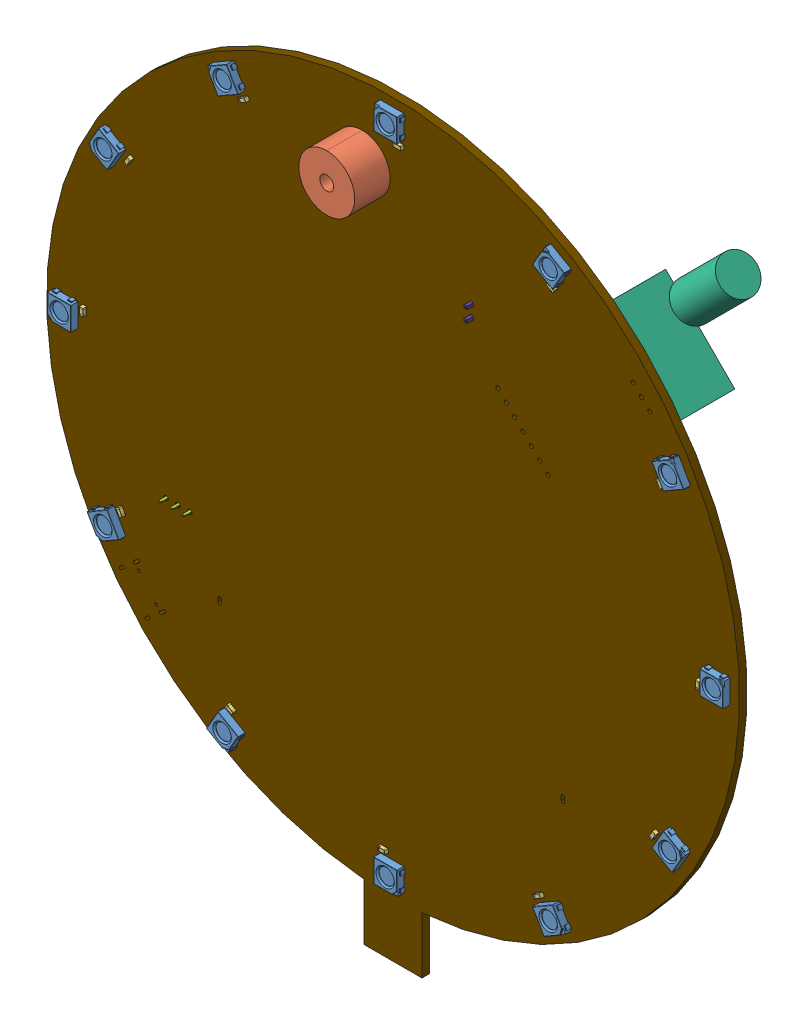
SolidWorks assembly Semafor2, configuration Výchozí. Lengths in mm.
Overall size (148.79 160.68 28.8).
170 component instances, 18 part files, 0 mates.
Components (placement in the parent):
- Semafor2.step-1: Semafor2.step [Výchozí] at origin size (148.79 160.68 28.8)
  - LED_WS2812B_PLCC4_5.0x5.0mm_P3.2mm.step-1: LED_WS2812B_PLCC4_5.0x5.0mm_P3.2mm.step [Výchozí] at (-39.4282 65.1 1.65) x (0.5 0.866025 0) z (0 0 1) size (5.4 5 1.6)
    - SOLID.step-1: SOLID.step [Výchozí] at origin size (5.4 5 1.6)
  - Piezo.step-1: Piezo.step [Výchozí] at (-106.6 158.895 1.65) x (1 0 0) z (0 -1 0) size (12 7.6 12)
    - SOLID-0.step-1: SOLID-0.step [Výchozí] at origin size (12 7.6 12)
  - LED_WS2812B_PLCC4_5.0x5.0mm_P3.2mm.step-2: LED_WS2812B_PLCC4_5.0x5.0mm_P3.2mm.step [Výchozí] at (-30.05 100.1 1.65) x (0 1 0) z (0 0 1) size (5.4 5 1.6)
    - SOLID.step-1: SOLID.step [Výchozí] at origin size (5.4 5 1.6)
  - LED_WS2812B_PLCC4_5.0x5.0mm_P3.2mm.step-3: LED_WS2812B_PLCC4_5.0x5.0mm_P3.2mm.step [Výchozí] at (-170.05 100.1 1.65) x (0 -1 0) z (0 0 1) size (5.4 5 1.6)
    - SOLID.step-1: SOLID.step [Výchozí] at origin size (5.4 5 1.6)
  - C_0603_1608Metric.step-1: C_0603_1608Metric.step [Výchozí] at (-101.75 33.8 1.65) size (1.6 0.8 0.8)
    - SOLID-1.step-1: SOLID-1.step [Výchozí] at origin size (1.6 0.8 0.8)
  - C_0603_1608Metric.step-2: C_0603_1608Metric.step [Výchozí] at (-43.5875 65.6288 1.65) x (0.5 0.866025 0) z (0 0 1) size (1.6 0.8 0.8)
    - SOLID-1.step-1: SOLID-1.step [Výchozí] at origin size (1.6 0.8 0.8)
  - C_0603_1608Metric.step-3: C_0603_1608Metric.step [Výchozí] at (-134.4288 43.6125 1.65) x (0.866025 -0.5 0) z (0 0 1) size (1.6 0.8 0.8)
    - SOLID-1.step-1: SOLID-1.step [Výchozí] at origin size (1.6 0.8 0.8)
  - C_0603_1608Metric.step-4: C_0603_1608Metric.step [Výchozí] at (-166.15 101.75 1.65) x (0 -1 0) z (0 0 1) size (1.6 0.8 0.8)
    - SOLID-1.step-1: SOLID-1.step [Výchozí] at origin size (1.6 0.8 0.8)
  - LED_WS2812B_PLCC4_5.0x5.0mm_P3.2mm.step-4: LED_WS2812B_PLCC4_5.0x5.0mm_P3.2mm.step [Výchozí] at (-100.05 30.1 1.65) size (5.4 5 1.6)
    - SOLID.step-1: SOLID.step [Výchozí] at origin size (5.4 5 1.6)
  - C_0603_1608Metric.step-5: C_0603_1608Metric.step [Výchozí] at (-158.05 68.5 1.65) x (0.5 -0.866025 0) z (0 0 1) size (1.6 0.8 0.8)
    - SOLID-1.step-1: SOLID-1.step [Výchozí] at origin size (1.6 0.8 0.8)
  - C_0603_1608Metric.step-6: C_0603_1608Metric.step [Výchozí] at (-68.35 41.95 1.65) x (0.866025 0.5 0) z (0 0 1) size (1.6 0.8 0.8)
    - SOLID-1.step-1: SOLID-1.step [Výchozí] at origin size (1.6 0.8 0.8)
  - LED_WS2812B_PLCC4_5.0x5.0mm_P3.2mm.step-5: LED_WS2812B_PLCC4_5.0x5.0mm_P3.2mm.step [Výchozí] at (-100.05 170.1 1.65) x (-1 0 0) z (0 0 1) size (5.4 5 1.6)
    - SOLID.step-1: SOLID.step [Výchozí] at origin size (5.4 5 1.6)
  - LED_WS2812B_PLCC4_5.0x5.0mm_P3.2mm.step-6: LED_WS2812B_PLCC4_5.0x5.0mm_P3.2mm.step [Výchozí] at (-39.4282 135.1 1.65) x (-0.5 0.866025 0) z (0 0 1) size (5.4 5 1.6)
    - SOLID.step-1: SOLID.step [Výchozí] at origin size (5.4 5 1.6)
  - LED_WS2812B_PLCC4_5.0x5.0mm_P3.2mm.step-7: LED_WS2812B_PLCC4_5.0x5.0mm_P3.2mm.step [Výchozí] at (-160.6718 65.1 1.65) x (0.5 -0.866025 0) z (0 0 1) size (5.4 5 1.6)
    - SOLID.step-1: SOLID.step [Výchozí] at origin size (5.4 5 1.6)
  - LED_WS2812B_PLCC4_5.0x5.0mm_P3.2mm.step-8: LED_WS2812B_PLCC4_5.0x5.0mm_P3.2mm.step [Výchozí] at (-65.05 39.4782 1.65) x (0.866025 0.5 0) z (0 0 1) size (5.4 5 1.6)
    - SOLID.step-1: SOLID.step [Výchozí] at origin size (5.4 5 1.6)
  - C_0603_1608Metric.step-7: C_0603_1608Metric.step [Výchozí] at (-65.45 156.55 1.65) x (-0.866025 0.5 0) z (0 0 1) size (1.6 0.8 0.8)
    - SOLID-1.step-1: SOLID-1.step [Výchozí] at origin size (1.6 0.8 0.8)
  - C_0603_1608Metric.step-8: C_0603_1608Metric.step [Výchozí] at (-33.9 98.45 1.65) x (0 1 0) z (0 0 1) size (1.6 0.8 0.8)
    - SOLID-1.step-1: SOLID-1.step [Výchozí] at origin size (1.6 0.8 0.8)
  - C_0603_1608Metric.step-9: C_0603_1608Metric.step [Výchozí] at (-98.4 166.3 1.65) x (-1 0 0) z (0 0 1) size (1.6 0.8 0.8)
    - SOLID-1.step-1: SOLID-1.step [Výchozí] at origin size (1.6 0.8 0.8)
  - LED_WS2812B_PLCC4_5.0x5.0mm_P3.2mm.step-9: LED_WS2812B_PLCC4_5.0x5.0mm_P3.2mm.step [Výchozí] at (-160.6718 135.1 1.65) x (-0.5 -0.866025 0) z (0 0 1) size (5.4 5 1.6)
    - SOLID.step-1: SOLID.step [Výchozí] at origin size (5.4 5 1.6)
  - LED_WS2812B_PLCC4_5.0x5.0mm_P3.2mm.step-10: LED_WS2812B_PLCC4_5.0x5.0mm_P3.2mm.step [Výchozí] at (-65.05 160.7218 1.65) x (-0.866025 0.5 0) z (0 0 1) size (5.4 5 1.6)
    - SOLID.step-1: SOLID.step [Výchozí] at origin size (5.4 5 1.6)
  - C_0603_1608Metric.step-10: C_0603_1608Metric.step [Výchozí] at (-156.35 134.6 1.65) x (-0.5 -0.866025 0) z (0 0 1) size (1.6 0.8 0.8)
    - SOLID-1.step-1: SOLID-1.step [Výchozí] at origin size (1.6 0.8 0.8)
  - LED_WS2812B_PLCC4_5.0x5.0mm_P3.2mm.step-11: LED_WS2812B_PLCC4_5.0x5.0mm_P3.2mm.step [Výchozí] at (-135.05 160.7218 1.65) x (-0.866025 -0.5 0) z (0 0 1) size (5.4 5 1.6)
    - SOLID.step-1: SOLID.step [Výchozí] at origin size (5.4 5 1.6)
  - C_0603_1608Metric.step-11: C_0603_1608Metric.step [Výchozí] at (-131.65 158.3 1.65) x (-0.866025 -0.5 0) z (0 0 1) size (1.6 0.8 0.8)
    - SOLID-1.step-1: SOLID-1.step [Výchozí] at origin size (1.6 0.8 0.8)
  - C_0603_1608Metric.step-12: C_0603_1608Metric.step [Výchozí] at (-42.05 131.8 1.65) x (-0.5 0.866025 0) z (0 0 1) size (1.6 0.8 0.8)
    - SOLID-1.step-1: SOLID-1.step [Výchozí] at origin size (1.6 0.8 0.8)
  - LED_WS2812B_PLCC4_5.0x5.0mm_P3.2mm.step-12: LED_WS2812B_PLCC4_5.0x5.0mm_P3.2mm.step [Výchozí] at (-135.05 39.4782 1.65) x (0.866025 -0.5 0) z (0 0 1) size (5.4 5 1.6)
    - SOLID.step-1: SOLID.step [Výchozí] at origin size (5.4 5 1.6)
  - R_0603_1608Metric.step-1: R_0603_1608Metric.step [Výchozí] at (-119.75 147.925 -0.05) x (0 -1 0) z (0 0 -1) size (1.6 0.8 0.45)
    - SOLID-2.step-1: SOLID-2.step [Výchozí] at origin size (1.6 0.8 0.45)
  - R_0603_1608Metric.step-2: R_0603_1608Metric.step [Výchozí] at (-115.95 147.9 -0.05) x (0 -1 0) z (0 0 -1) size (1.6 0.8 0.45)
    - SOLID-2.step-1: SOLID-2.step [Výchozí] at origin size (1.6 0.8 0.45)
  - D_SOD-123.step-1: D_SOD-123.step [Výchozí] at (-130.0125 82.075 -0.05) x (-1 0 0) z (0 0 -1) size (3.8 1.6 1.25)
    - SOLID-3.step-1: SOLID-3.step [Výchozí] at origin size (3.8 1.6 1.25)
  - E22_900T22D.step-1: E22_900T22D.step [Výchozí] at (-60.45 137.7711 -0.05) x (-0.707107 -0.707107 0) z (0 0 -1) size (50 21 17.3)
    - SOLID-4.step-1: SOLID-4.step [Výchozí] at origin size (50 21 17.3)
  - D_SOD-123.step-2: D_SOD-123.step [Výchozí] at (-96.1 29.05 -0.05) x (0 -1 0) z (0 0 -1) size (3.8 1.6 1.25)
    - SOLID-3.step-1: SOLID-3.step [Výchozí] at origin size (3.8 1.6 1.25)
  - PinSocket_1x03_P2.54mm_Vertical.step-1: PinSocket_1x03_P2.54mm_Vertical.step [Výchozí] at (-143.675 75.375 -0.05) x (0 1 0) z (0 0 -1) size (2.54 7.62 10.1)
    - SOLID-5.step-1: SOLID-5.step [Výchozí] at origin size (2.54 7.62 10.1)
  - D_SOD-323.step-1: D_SOD-323.step [Výchozí] at (-142.6 58.8 -0.05) x (0.642788 -0.766044 0) z (0 0 -1) size (2.5 1.25 1.1)
    - SOLID-6.step-1: SOLID-6.step [Výchozí] at origin size (2.5 1.25 1.1)
  - C_0603_1608Metric.step-13: C_0603_1608Metric.step [Výchozí] at (-158.9591 131.0993 -0.05) x (-0.939693 0.34202 0) z (0 0 -1) size (1.6 0.8 0.8)
    - SOLID-1.step-1: SOLID-1.step [Výchozí] at origin size (1.6 0.8 0.8)
  - R_0603_1608Metric.step-3: R_0603_1608Metric.step [Výchozí] at (-83.3756 132.275 -0.05) x (-1 0 0) z (0 0 -1) size (1.6 0.8 0.45)
    - SOLID-2.step-1: SOLID-2.step [Výchozí] at origin size (1.6 0.8 0.45)
  - R_0603_1608Metric.step-4: R_0603_1608Metric.step [Výchozí] at (-118.05 147.9 -0.05) x (0 -1 0) z (0 0 -1) size (1.6 0.8 0.45)
    - SOLID-2.step-1: SOLID-2.step [Výchozí] at origin size (1.6 0.8 0.45)
  - R_0603_1608Metric.step-5: R_0603_1608Metric.step [Výchozí] at (-116.95 136.3 -0.05) x (0 -1 0) z (0 0 -1) size (1.6 0.8 0.45)
    - SOLID-2.step-1: SOLID-2.step [Výchozí] at origin size (1.6 0.8 0.45)
  - C_0805_2012Metric.step-1: C_0805_2012Metric.step [Výchozí] at (-152.9591 126.5493 -0.05) x (0.939693 -0.34202 0) z (0 0 -1) size (2 1.25 1.25)
    - SOLID-7.step-1: SOLID-7.step [Výchozí] at origin size (2 1.25 1.25)
  - LED_0603_1608Metric.step-1: LED_0603_1608Metric.step [Výchozí] at (-147.525 84.025 -0.05) x (-1 0 0) z (0 0 -1) size (1.6 0.8 1.1)
    - SOLID-8.step-1: SOLID-8.step [Výchozí] at origin size (1.6 0.8 1.1)
  - SOT-23.step-1: SOT-23.step [Výchozí] at (-83.3256 136.55 -0.05) x (0 1 0) z (0 0 -1) size (2.5 3 1.2)
    - SOLID-9.step-1: SOLID-9.step [Výchozí] at origin size (2.5 3 1.2)
  - SOT-23.step-2: SOT-23.step [Výchozí] at (-146.9091 122.0993 -0.05) x (0.939693 -0.34202 0) z (0 0 -1) size (2.5 3 1.2)
    - SOLID-9.step-1: SOLID-9.step [Výchozí] at origin size (2.5 3 1.2)
  - R_0603_1608Metric.step-6: R_0603_1608Metric.step [Výchozí] at (-120.725 43.975 -0.05) x (-1 0 0) z (0 0 -1) size (1.6 0.8 0.45)
    - SOLID-2.step-1: SOLID-2.step [Výchozí] at origin size (1.6 0.8 0.45)
  - C_0805_2012Metric.step-2: C_0805_2012Metric.step [Výchozí] at (-159.7591 129.0993 -0.05) x (-0.939693 0.34202 0) z (0 0 -1) size (2 1.25 1.25)
    - SOLID-7.step-1: SOLID-7.step [Výchozí] at origin size (2 1.25 1.25)
  - R_0603_1608Metric.step-7: R_0603_1608Metric.step [Výchozí] at (-120.15 136.3 -0.05) x (0 -1 0) z (0 0 -1) size (1.6 0.8 0.45)
    - SOLID-2.step-1: SOLID-2.step [Výchozí] at origin size (1.6 0.8 0.45)
  - D_SOD-323.step-2: D_SOD-323.step [Výchozí] at (-147.5 62.875 -0.05) x (-0.766044 -0.642788 0) z (0 0 -1) size (2.5 1.25 1.1)
    - SOLID-6.step-1: SOLID-6.step [Výchozí] at origin size (2.5 1.25 1.1)
  - C_0805_2012Metric.step-3: C_0805_2012Metric.step [Výchozí] at (-128.3875 78.75 -0.05) x (0 -1 0) z (0 0 -1) size (2 1.25 1.25)
    - SOLID-7.step-1: SOLID-7.step [Výchozí] at origin size (2 1.25 1.25)
  - R_0603_1608Metric.step-8: R_0603_1608Metric.step [Výchozí] at (-143.0091 117.4493 -0.05) x (0.939693 -0.34202 0) z (0 0 -1) size (1.6 0.8 0.45)
    - SOLID-2.step-1: SOLID-2.step [Výchozí] at origin size (1.6 0.8 0.45)
  - LED_0603_1608Metric.step-2: LED_0603_1608Metric.step [Výchozí] at (-109.425 43.2125 -0.05) x (0 -1 0) z (0 0 -1) size (1.6 0.8 1.1)
    - SOLID-8.step-1: SOLID-8.step [Výchozí] at origin size (1.6 0.8 1.1)
  - R_0603_1608Metric.step-9: R_0603_1608Metric.step [Výchozí] at (-135.1875 77.025 -0.05) x (0 1 0) z (0 0 -1) size (1.6 0.8 0.45)
    - SOLID-2.step-1: SOLID-2.step [Výchozí] at origin size (1.6 0.8 0.45)
  - USB_C.step-1: USB_C.step [Výchozí] at (-154.7 55.1 -0.05) x (-0.766044 -0.642788 0) z (0 0 -1) size (7.5 9 3.5)
    - SOLID-10.step-1: SOLID-10.step [Výchozí] at origin size (7.5 9 3.5)
  - Battery_pack.step-1: Battery_pack.step [Výchozí] at (-99.9 62.1 -0.05) x (-1 0 0) z (0 0 -1) size (77 21 19.5)
    - SOLID-11.step-1: SOLID-11.step [Výchozí] at origin size (77 21 19.5)
  - LED_0603_1608Metric.step-3: LED_0603_1608Metric.step [Výchozí] at (-107.575 43.225 -0.05) x (0 -1 0) z (0 0 -1) size (1.6 0.8 1.1)
    - SOLID-8.step-1: SOLID-8.step [Výchozí] at origin size (1.6 0.8 1.1)
  - R_0603_1608Metric.step-10: R_0603_1608Metric.step [Výchozí] at (-144.1125 87.05 -0.05) x (1 0 0) z (0 0 -1) size (1.6 0.8 0.45)
    - SOLID-2.step-1: SOLID-2.step [Výchozí] at origin size (1.6 0.8 0.45)
  - D_SOD-123.step-3: D_SOD-123.step [Výchozí] at (-117.975 155.17 -0.05) x (-1 0 0) z (0 0 -1) size (3.8 1.6 1.25)
    - SOLID-3.step-1: SOLID-3.step [Výchozí] at origin size (3.8 1.6 1.25)
  - R_0603_1608Metric.step-11: R_0603_1608Metric.step [Výchozí] at (-114.175 160.345 -0.05) x (0 -1 0) z (0 0 -1) size (1.6 0.8 0.45)
    - SOLID-2.step-1: SOLID-2.step [Výchozí] at origin size (1.6 0.8 0.45)
  - R_0603_1608Metric.step-12: R_0603_1608Metric.step [Výchozí] at (-150.9091 118.3743 -0.05) x (-0.34202 -0.939693 0) z (0 0 -1) size (1.6 0.8 0.45)
    - SOLID-2.step-1: SOLID-2.step [Výchozí] at origin size (1.6 0.8 0.45)
  - D_SOD-323.step-3: D_SOD-323.step [Výchozí] at (-98.4 29.65 -0.05) x (0 1 0) z (0 0 -1) size (2.5 1.25 1.1)
    - SOLID-6.step-1: SOLID-6.step [Výchozí] at origin size (2.5 1.25 1.1)
  - SOIC-14_3.9x8.7mm_P1.27mm.step-1: SOIC-14_3.9x8.7mm_P1.27mm.step [Výchozí] at (-118.5 142.1 -0.05) x (0 -1 0) z (0 0 -1) size (6 8.7 1.75)
    - SOLID-12.step-1: SOLID-12.step [Výchozí] at origin size (6 8.7 1.75)
  - C_0603_1608Metric.step-14: C_0603_1608Metric.step [Výchozí] at (-124.55 142.3493 -0.05) x (0 -1 0) z (0 0 -1) size (1.6 0.8 0.8)
    - SOLID-1.step-1: SOLID-1.step [Výchozí] at origin size (1.6 0.8 0.8)
  - R_0603_1608Metric.step-13: R_0603_1608Metric.step [Výchozí] at (-147.4841 125.4493 -0.05) x (0.939693 -0.34202 0) z (0 0 -1) size (1.6 0.8 0.45)
    - SOLID-2.step-1: SOLID-2.step [Výchozí] at origin size (1.6 0.8 0.45)
  - C_0805_2012Metric.step-4: C_0805_2012Metric.step [Výchozí] at (-126.5 142.3993 -0.05) x (0 -1 0) z (0 0 -1) size (2 1.25 1.25)
    - SOLID-7.step-1: SOLID-7.step [Výchozí] at origin size (2 1.25 1.25)
  - R_0603_1608Metric.step-14: R_0603_1608Metric.step [Výchozí] at (-139.1625 81.2 -0.05) x (0 -1 0) z (0 0 -1) size (1.6 0.8 0.45)
    - SOLID-2.step-1: SOLID-2.step [Výchozí] at origin size (1.6 0.8 0.45)
  - R_0603_1608Metric.step-15: R_0603_1608Metric.step [Výchozí] at (-132.6875 77.875 -0.05) x (1 0 0) z (0 0 -1) size (1.6 0.8 0.45)
    - SOLID-2.step-1: SOLID-2.step [Výchozí] at origin size (1.6 0.8 0.45)
  - SOT-23.step-3: SOT-23.step [Výchozí] at (-118.675 160.445 -0.05) x (-1 0 0) z (0 0 -1) size (2.5 3 1.2)
    - SOLID-9.step-1: SOLID-9.step [Výchozí] at origin size (2.5 3 1.2)
  - R_0402_1005Metric.step-1: R_0402_1005Metric.step [Výchozí] at (-150.45 61 -0.05) x (0.766044 0.642788 0) z (0 0 -1) size (1 0.5 0.35)
    - SOLID-13.step-1: SOLID-13.step [Výchozí] at origin size (1 0.5 0.35)
  - C_0805_2012Metric.step-5: C_0805_2012Metric.step [Výchozí] at (-114.675 48.525 -0.05) x (-1 0 0) z (0 0 -1) size (2 1.25 1.25)
    - SOLID-7.step-1: SOLID-7.step [Výchozí] at origin size (2 1.25 1.25)
  - R_0603_1608Metric.step-16: R_0603_1608Metric.step [Výchozí] at (-152.1341 114.7493 -0.05) x (-0.34202 -0.939693 0) z (0 0 -1) size (1.6 0.8 0.45)
    - SOLID-2.step-1: SOLID-2.step [Výchozí] at origin size (1.6 0.8 0.45)
  - C_0603_1608Metric.step-15: C_0603_1608Metric.step [Výchozí] at (-78.4756 143.175 -0.05) x (0 -1 0) z (0 0 -1) size (1.6 0.8 0.8)
    - SOLID-1.step-1: SOLID-1.step [Výchozí] at origin size (1.6 0.8 0.8)
  - C_0805_2012Metric.step-6: C_0805_2012Metric.step [Výchozí] at (-120.625 46.525 -0.05) x (-1 0 0) z (0 0 -1) size (2 1.25 1.25)
    - SOLID-7.step-1: SOLID-7.step [Výchozí] at origin size (2 1.25 1.25)
  - R_0603_1608Metric.step-17: R_0603_1608Metric.step [Výchozí] at (-115.3 136.3 -0.05) x (0 1 0) z (0 0 -1) size (1.6 0.8 0.45)
    - SOLID-2.step-1: SOLID-2.step [Výchozí] at origin size (1.6 0.8 0.45)
  - SOT-23-5.step-1: SOT-23-5.step [Výchozí] at (-135.2875 81.1 -0.05) x (-1 0 0) z (0 0 -1) size (2.8 2.9 1.55)
    - SOLID-14.step-1: SOLID-14.step [Výchozí] at origin size (2.8 2.9 1.55)
  - R_0402_1005Metric.step-2: R_0402_1005Metric.step [Výchozí] at (-148.35 58.75 -0.05) x (0.766044 0.642788 0) z (0 0 -1) size (1 0.5 0.35)
    - SOLID-13.step-1: SOLID-13.step [Výchozí] at origin size (1 0.5 0.35)
  - C_0805_2012Metric.step-7: C_0805_2012Metric.step [Výchozí] at (-136.7875 84.075 -0.05) x (1 0 0) z (0 0 -1) size (2 1.25 1.25)
    - SOLID-7.step-1: SOLID-7.step [Výchozí] at origin size (2 1.25 1.25)
  - PinHeader_1x02_P2.54mm_Vertical.step-1: PinHeader_1x02_P2.54mm_Vertical.step [Výchozí] at (-83.2244 144.25 -0.05) x (-1 0 0) z (0 0 -1) size (2.54 5.08 11.54)
    - SOLID-15.step-1: SOLID-15.step [Výchozí] at origin size (2.54 5.08 11.54)
  - D_SOD-323.step-4: D_SOD-323.step [Výchozí] at (-146.2 61.275 -0.05) x (-0.766044 -0.642788 0) z (0 0 -1) size (2.5 1.25 1.1)
    - SOLID-6.step-1: SOLID-6.step [Výchozí] at origin size (2.5 1.25 1.1)
  - LED_0603_1608Metric.step-4: LED_0603_1608Metric.step [Výchozí] at (-147.5125 87.075 -0.05) x (-1 0 0) z (0 0 -1) size (1.6 0.8 1.1)
    - SOLID-8.step-1: SOLID-8.step [Výchozí] at origin size (1.6 0.8 1.1)
  - R_0603_1608Metric.step-18: R_0603_1608Metric.step [Výchozí] at (-156.1591 128.8493 -0.05) x (0.939693 -0.34202 0) z (0 0 -1) size (1.6 0.8 0.45)
    - SOLID-2.step-1: SOLID-2.step [Výchozí] at origin size (1.6 0.8 0.45)
  - R_0603_1608Metric.step-19: R_0603_1608Metric.step [Výchozí] at (-144.15 84.05 -0.05) x (1 0 0) z (0 0 -1) size (1.6 0.8 0.45)
    - SOLID-2.step-1: SOLID-2.step [Výchozí] at origin size (1.6 0.8 0.45)
  - R_0603_1608Metric.step-20: R_0603_1608Metric.step [Výchozí] at (-110.275 40.775 -0.05) x (1 0 0) z (0 0 -1) size (1.6 0.8 0.45)
    - SOLID-2.step-1: SOLID-2.step [Výchozí] at origin size (1.6 0.8 0.45)
  - D_SOD-123.step-4: D_SOD-123.step [Výchozí] at (-144.6 55.65 -0.05) x (-0.766044 -0.642788 0) z (0 0 -1) size (3.8 1.6 1.25)
    - SOLID-3.step-1: SOLID-3.step [Výchozí] at origin size (3.8 1.6 1.25)
  - SOT-23.step-4: SOT-23.step [Výchozí] at (-143.8591 114.7993 -0.05) x (0.939693 -0.34202 0) z (0 0 -1) size (2.5 3 1.2)
    - SOLID-9.step-1: SOLID-9.step [Výchozí] at origin size (2.5 3 1.2)
  - R_0603_1608Metric.step-21: R_0603_1608Metric.step [Výchozí] at (-155.1091 131.9243 -0.05) x (-0.34202 -0.939693 0) z (0 0 -1) size (1.6 0.8 0.45)
    - SOLID-2.step-1: SOLID-2.step [Výchozí] at origin size (1.6 0.8 0.45)
  - R_0603_1608Metric.step-22: R_0603_1608Metric.step [Výchozí] at (-118.55 136.3 -0.05) x (0 -1 0) z (0 0 -1) size (1.6 0.8 0.45)
    - SOLID-2.step-1: SOLID-2.step [Výchozí] at origin size (1.6 0.8 0.45)
  - R_0603_1608Metric.step-23: R_0603_1608Metric.step [Výchozí] at (-121.75 136.2993 -0.05) x (0 -1 0) z (0 0 -1) size (1.6 0.8 0.45)
    - SOLID-2.step-1: SOLID-2.step [Výchozí] at origin size (1.6 0.8 0.45)
  - D_SOD-123.step-5: D_SOD-123.step [Výchozí] at (-74.5506 143.175 -0.05) x (0 -1 0) z (0 0 -1) size (3.8 1.6 1.25)
    - SOLID-3.step-1: SOLID-3.step [Výchozí] at origin size (3.8 1.6 1.25)
  - Semafor PCB.step-1: Semafor PCB.step [Výchozí] at origin size (148.79 160.68 1.6)
